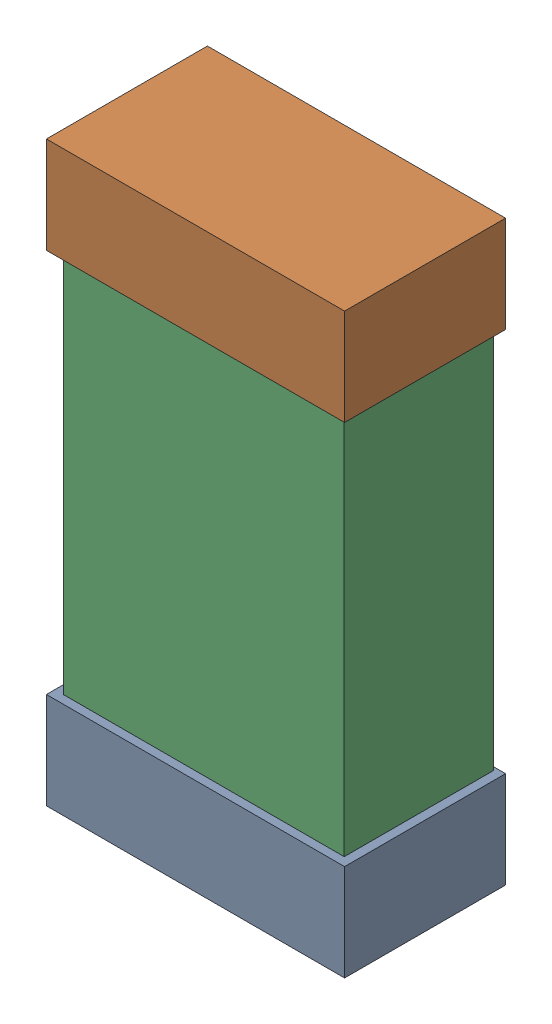
SolidWorks assembly R39, configuration Default. Lengths in mm.
Overall size (0.85 1.65 0.46).
6 component instances, 2 part files, 0 mates.
Components (placement in the parent):
- 432138512_26-1: 432138512_26 [Default] at (12.6999 61.3641 -0.8715) size (0.85 0.28 0.46)
  - Extruded-1: Extruded [Default] at origin size (0.85 0.28 0.46)
- 432138512_27-1: 432138512_27 [Default] at (12.6999 62.7357 -0.8715) size (0.85 0.28 0.46)
  - Extruded-1: Extruded [Default] at origin size (0.85 0.28 0.46)
- 432124816_13-1: 432124816_13 [Default] at (12.6999 62.0499 -0.8615) size (0.8 1.5 0.42)
  - Extruded (1)-1: Extruded (1) [Default] at origin size (0.8 1.5 0.42)
